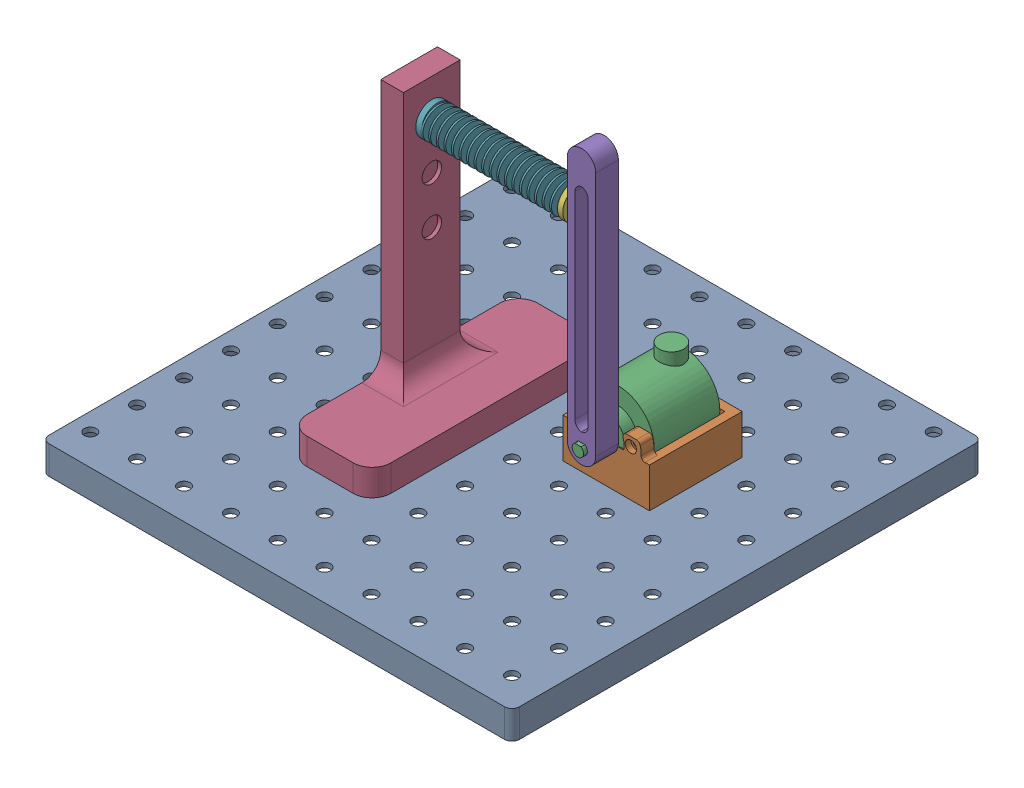
SolidWorks assembly pend1 assembly 2, configuration Default. Lengths in mm.
Overall size (249 175.7 249).
6 component instances, 6 part files, 13 mates.
Components (placement in the parent):
- pegboard-1: pegboard [Default] at (24.5062 48.8373 149.2658) x (1 0 0) z (0 0 -1) size (249 15 249)
- encoder holder-1: encoder holder [Default] at (-36.5243 59.3989 78.3398) size (45.82 36.12 49.09)
- taiss encoder-1: taiss encoder [Default] at (55.5947 72.0373 116.8398) size (38.3 44.15 56)
- pendulum1 body-1: pendulum1 body [Default] at (-51.5049 59.3989 75.8353) size (44.38 155 122)
- pendulum1-1: pendulum1 [Default] at (53.7399 99.4567 158.9094) size (15 145 12)
- example slinky-1: example slinky [Default] at (-26.8012 177.6292 164.7444) x (0 -0.192316 -0.981333) z (0 -0.981333 0.192316) size (17 77.8 17)
Mates (geometry in assembly coordinates):
- Concentric1: concentric aligned: cylinder of pegboard-1 through (68.4895 36.3373 146.1898) axis (0 1 0) radius 3.2; cylinder of encoder holder-1 through (68.4895 41.8373 146.1898) axis (0 1 0) radius 3.25
- Concentric2: concentric aligned: cylinder of pegboard-1 through (43.6895 36.3373 121.3898) axis (0 1 0) radius 3.2; cylinder of encoder holder-1 through (43.6895 41.8373 121.3898) axis (0 1 0) radius 3.25
- Coincident1: coincident anti-aligned: plane of pegboard-1 through (24.5062 48.8373 149.2658) normal (0 1 0); plane of encoder holder-1 through (-36.5243 48.8373 78.3398) normal (0 -1 0)
- Concentric3: concentric anti-aligned: cylinder of encoder holder-1 through (55.5947 72.0373 116.8398) axis (0 0 1) radius 19; cylinder of taiss encoder-1 through (55.5947 72.0373 151.5898) axis (0 0 -1) radius 19.15
- Concentric4: concentric aligned: cylinder of pegboard-1 through (-30.7105 36.3373 220.5898) axis (0 1 0) radius 3.2; cylinder of pendulum1 body-1 through (-30.7105 41.8373 220.5898) axis (0 1 0) radius 3.15
- Concentric5: concentric aligned: cylinder of pegboard-1 through (-5.9105 36.3373 195.7898) axis (0 1 0) radius 3.2; cylinder of pendulum1 body-1 through (-5.9105 41.8373 195.7898) axis (0 1 0) radius 3.15
- Coincident2: coincident anti-aligned: plane of pegboard-1 through (24.5062 48.8373 149.2658) normal (0 1 0); plane of pendulum1 body-1 through (-51.5049 48.8373 75.8353) normal (0 -1 0)
- Concentric6: concentric anti-aligned: cylinder of taiss encoder-1 through (55.5947 72.0373 172.8398) axis (0 0 -1) radius 3; cylinder of pendulum1-1 through (55.5947 72.0373 135.9094) axis (0 0 1) radius 3.1
- Parallel1: parallel aligned: line of taiss encoder-1 through (53.9471 74.5444 172.8398) axis (0.999991 -0.004249 0); line of pendulum1-1 through (53.9176 74.6445 170.9094) axis (0.999991 -0.004249 0)
- Coincident6: coincident anti-aligned: plane of encoder holder-1 through (55.5947 72.0373 151.5898) normal (0 0 -1); plane of taiss encoder-1 through (55.5947 72.0373 151.5898) normal (0 0 1)
- Coincident7: coincident anti-aligned: circle of pendulum1 body-1; circle of example slinky-1
- Coincident8: coincident anti-aligned: plane of pendulum1 body-1 through (-29.8012 59.3989 75.8353) normal (1 0 0); plane of example slinky-1 through (-29.8133 174.7668 161.8169) normal (-1 0 0)
- Parallel2: parallel anti-aligned: plane of pendulum1-1 through (48.0947 202.0373 170.9094) normal (-1 0 0); plane of example slinky-1 through (47.9988 177.6292 164.7444) normal (1 0 0)
